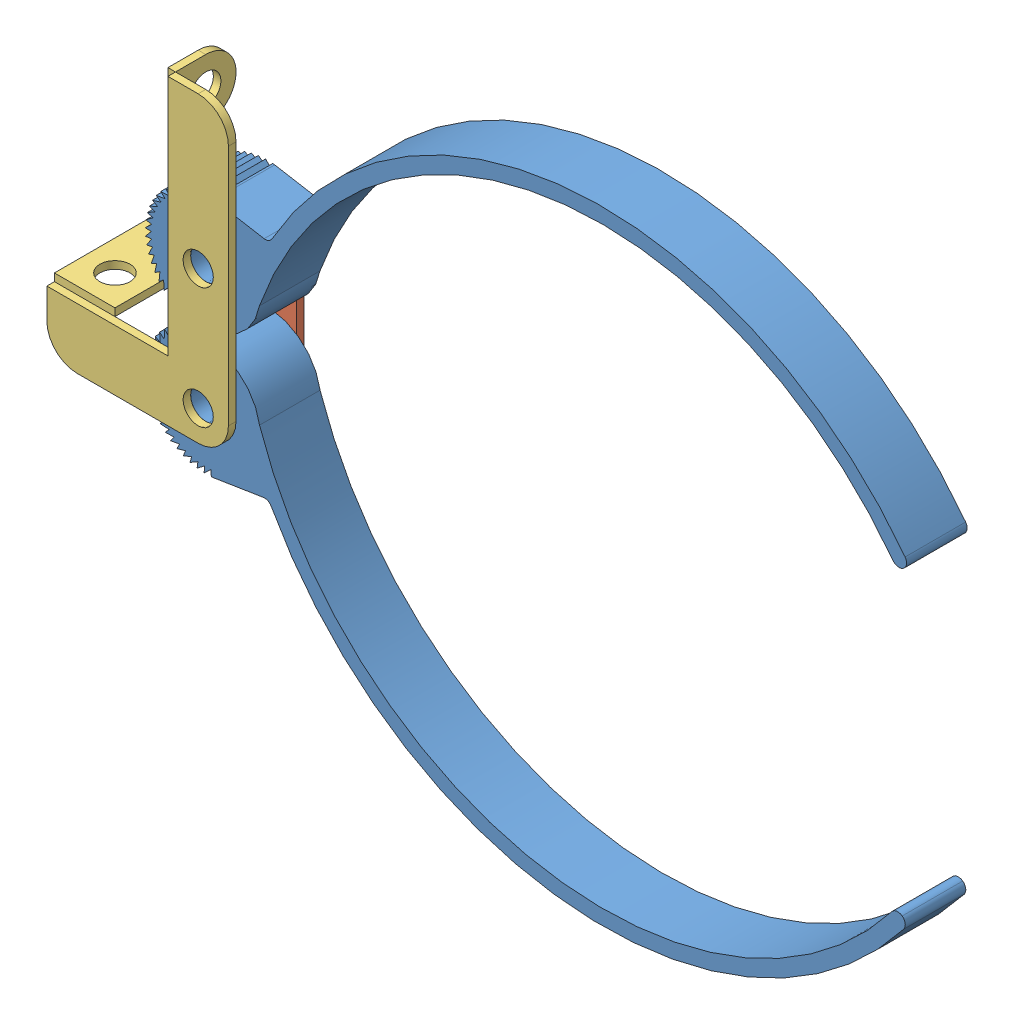
SolidWorks assembly L Bracket Leg Piece, configuration Default. Lengths in mm.
Overall size (182.68 161.1 39.69).
4 component instances, 3 part files, 7 mates.
Components (placement in the parent):
- Ratchet Clamp-1: Ratchet Clamp [Default] at (-38.643 62.0991 121.217) x (0.985286 -0.170911 0) z (0 0 1) size (154.32 79.38 12.7)
- Ratchet Clamp-2: Ratchet Clamp [Default] at (-38.643 36.6991 133.917) x (0.987582 0.157104 0) z (0 0 -1) size (154.32 79.38 12.7)
- L plate-2: L plate [Default] at (-32.293 30.3491 121.217) x (-1 0 0) z (0 0 -1) size (12.7 38.1 1.59)
- L plate with Tabs-1: L plate with Tabs [Default] at (-32.293 30.3491 135.5045) x (-1 0 0) z (0 0 -1) size (38.1 63.5 39.69)
Mates (geometry in assembly coordinates):
- Coincident3: coincident anti-aligned: plane of Ratchet Clamp-1 through (-38.643 62.0991 121.217) normal (0 0 -1); plane of L plate-2 through (-32.293 30.3491 121.217) normal (0 0 1)
- Coincident4: coincident anti-aligned: plane of Ratchet Clamp-2 through (-38.643 36.6991 121.217) normal (0 0 -1); plane of L plate-2 through (-32.293 30.3491 121.217) normal (0 0 1)
- Concentric3: concentric aligned: cylinder of Ratchet Clamp-2 through (-38.643 36.6991 121.217) axis (0 0 1) radius 3.175; cylinder of L plate-2 through (-38.643 36.6991 119.6295) axis (0 0 1) radius 3.175
- Concentric4: concentric anti-aligned: cylinder of Ratchet Clamp-1 through (-38.643 62.0991 133.917) axis (0 0 -1) radius 3.175; cylinder of L plate-2 through (-38.643 62.0991 119.6295) axis (0 0 1) radius 3.175
- Coincident5: coincident anti-aligned: plane of Ratchet Clamp-1 through (-38.643 62.0991 133.917) normal (0 0 1); plane of L plate with Tabs-1 through (-32.293 30.3491 133.917) normal (0 0 -1)
- Concentric5: concentric aligned: cylinder of Ratchet Clamp-2 through (-38.643 36.6991 121.217) axis (0 0 1) radius 3.175; cylinder of L plate with Tabs-1 through (-38.643 36.6991 133.917) axis (0 0 1) radius 3.175
- Concentric6: concentric anti-aligned: cylinder of Ratchet Clamp-1 through (-38.643 62.0991 133.917) axis (0 0 -1) radius 3.175; cylinder of L plate with Tabs-1 through (-38.643 62.0991 133.917) axis (0 0 1) radius 3.175
